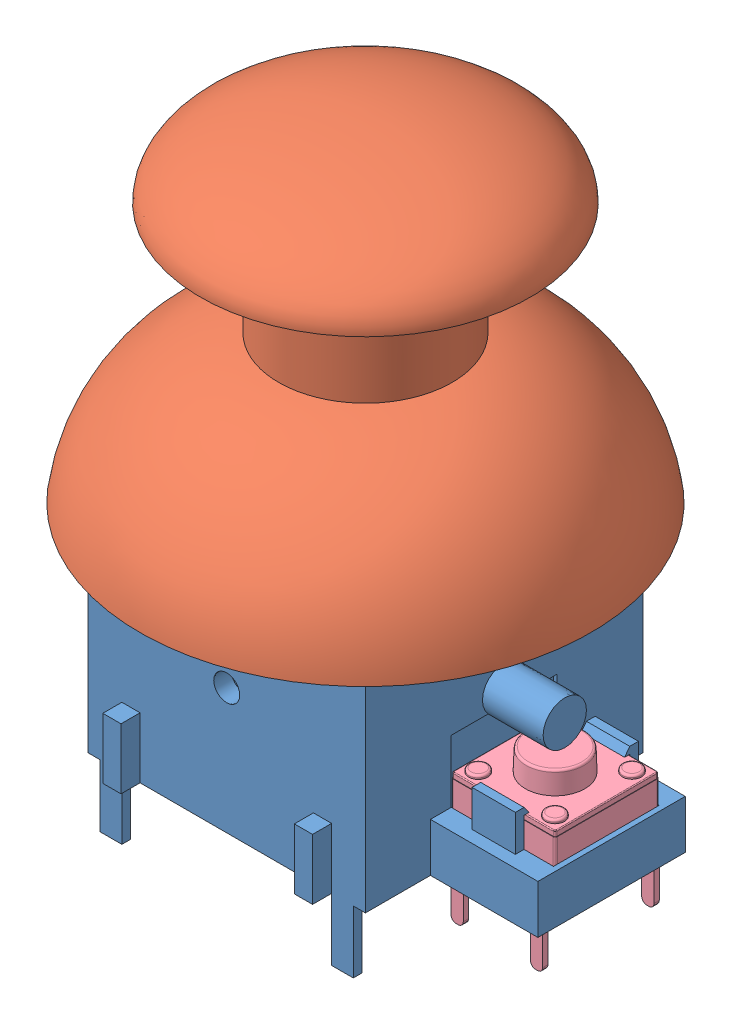
SolidWorks assembly Joystick, configuration Défaut. Lengths in mm.
Overall size (27.78 35.1 27.15).
5 component instances, 4 part files, 11 mates.
Components (placement in the parent):
- Mécanisme-1: Mécanisme [Défaut] at (4.6458 -13.2312 -0.55) size (22.2 23.1 17.1)
- Manche-1: Manche [Défaut] at (4.6458 -0.7312 -0.55) x (0.998969 0 -0.045407) z (0.045407 0 0.998969) size (26 19 26)
- Potentiometre-1: Potentiometre [Défaut] at (4.6458 -6.4812 -8.55) x (-1 0 0) z (0 0 -1) size (9.5 14.5 4)
- Potentiometre-2: Potentiometre [Défaut] at (-3.3542 -6.4812 -0.55) x (0 0 1) z (-1 0 0) size (9.5 14.5 4)
- tactileswitch-1: tactileswitch [Default] at (15.5423 -12.4312 -0.5965) x (0 0 -1) z (1 0 0) size (6.72 8.35 6.01)
Mates (geometry in assembly coordinates):
- Coïncidente1: coincident anti-aligned: plane of Mécanisme-1 through (4.6458 -12.4312 -0.55) normal (0 1 0); plane of tactileswitch-1 through (12.5387 -12.4312 -1.8982) normal (0 -1 0)
- Coïncidente2: coincident anti-aligned: plane of Mécanisme-1 through (18.5458 -6.8312 -3.6) normal (0 0 1); plane of tactileswitch-1 through (18.5458 -9.053 -3.6) normal (0 0 -1)
- Coïncidente3: coincident anti-aligned: plane of Mécanisme-1 through (18.5458 -6.8312 2.5) normal (-1 0 0); plane of tactileswitch-1 through (18.5458 -9.053 2.4071) normal (1 0 0)
- Coïncidente4: coincident anti-aligned: plane of Mécanisme-1 through (-3.3542 -1.2312 -8.55) normal (0 0 -1); plane of Potentiometre-1 through (4.6458 -6.4812 -8.55) normal (0 0 1)
- Parallèle1: parallel aligned: plane of Mécanisme-1 through (4.6458 -1.2312 -0.55) normal (0 1 0); plane of Potentiometre-1 through (-0.1042 -0.9812 -11.55) normal (0 1 0)
- Coaxiale1: concentric anti-aligned: circle of Mécanisme-1; circle of Potentiometre-1
- Coïncidente7: coincident anti-aligned: plane of Mécanisme-1 through (-3.3542 -1.2312 7.45) normal (-1 0 0); plane of Potentiometre-2 through (-3.3542 -6.4812 -0.55) normal (1 0 0)
- Coaxiale2: concentric anti-aligned: cylinder of Mécanisme-1 through (16.1458 -5.9812 -0.55) axis (-1 0 0) radius 1.25; cylinder of Potentiometre-2 through (-7.3542 -5.9812 -0.55) axis (1 0 0) radius 2
- Parallèle2: parallel aligned: plane of Mécanisme-1 through (4.6458 -1.2312 -0.55) normal (0 1 0); plane of Potentiometre-2 through (-6.3542 -0.9812 4.2) normal (0 1 0)
- Coaxiale3: concentric: cylinder of Mécanisme-1 through (4.6458 -1.2312 -0.55) axis (0 -1 0) radius 3.5; cylinder of Manche-1 through (4.6458 -0.7312 -0.55) axis (0 -1 0) radius 1
- Distance1: distance = 3.5 mm anti-aligned: plane of Manche-1 through (5.6448 2.2688 -0.5954) normal (0 -1 0); plane of Mécanisme-1 through (4.6458 -1.2312 -0.55) normal (0 1 0)
